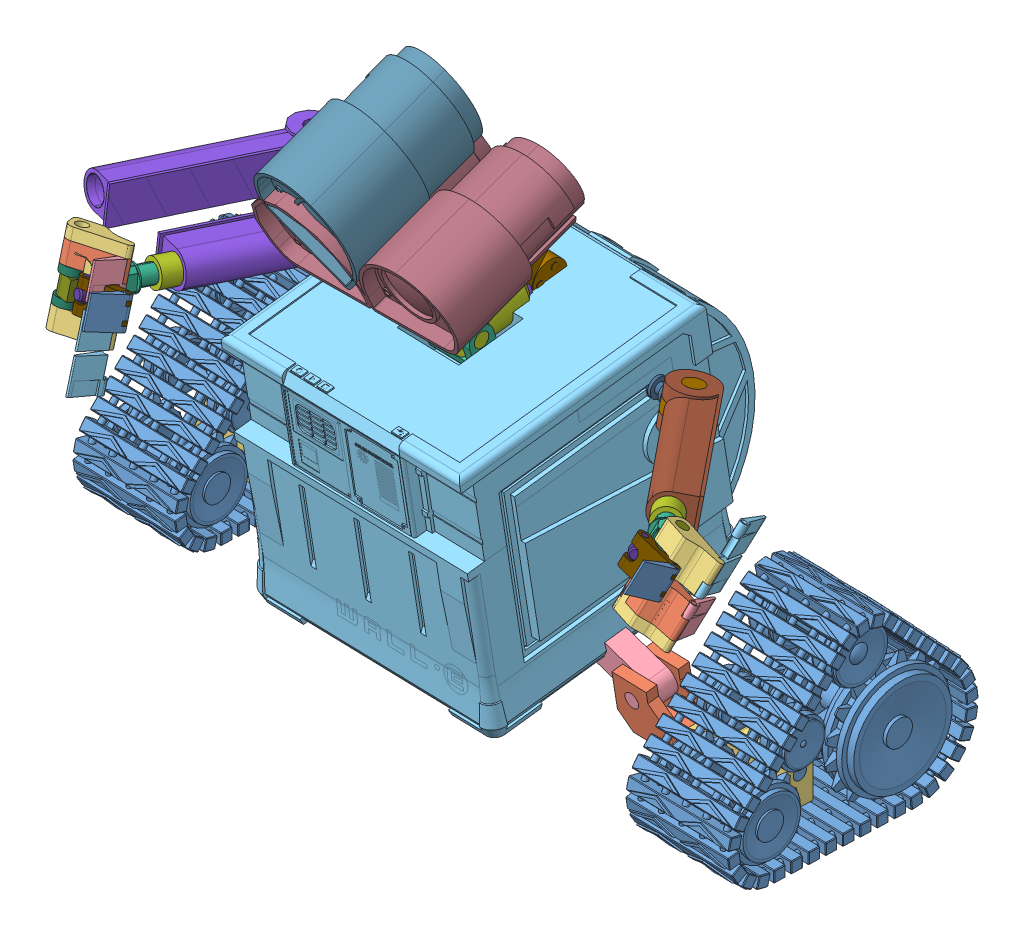
SolidWorks assembly Wall-E, configuration Default. Lengths in mm.
Overall size (1010.81 812.29 599.18).
52 component instances, 29 part files, 21 mates.
Components (placement in the parent):
- been links ^Wall-E-1: been links ^Wall-E [Default] at origin size (390.22 327.08 393.39) (virtual)
  - Leg2-1: Leg2 [Default] at (217.59 79.9141 -697.9774) x (0.99964 0 0.026846) z (-0.026526 -0.154085 0.987701) size (150 276.28 351.13)
  - Leg4-1: Leg4 [Default] at (37.1535 79.1519 -684.1405) x (0.99964 0 0.026846) z (-0.026526 -0.154085 0.987701) size (110 70 60)
  - Leg5-1: Leg5 [Default] at (37.2437 79.4124 -687.5004) x (0.99964 0 0.026846) z (-0.026846 0 0.99964) size (135 55 55.64)
  - Leg1-1: Leg1 [Default] at (-65.5734 118.3428 -680.7854) x (0.933881 -0.356281 -0.030501) z (-0.026526 -0.154085 0.987701) size (150 40 60)
- been rechts ^Wall-E-1: been rechts ^Wall-E [Default] at origin size (388.72 327.08 393.39) (virtual)
  - Leg2-1: Leg2 [Default] at (-587.65 80.7609 -719.4707) x (0.99964 0 0.026846) z (-0.026526 -0.154085 0.987701) size (150 276.28 351.13)
  - Leg4-1: Leg4 [Default] at (-408.2163 79.9987 -695.9692) x (-0.99964 0 -0.026846) z (0.026526 0.154085 -0.987701) size (110 70 60)
  - Leg5-1: Leg5 [Default] at (-408.126 80.2592 -699.329) x (-0.99964 0 -0.026846) z (0.026846 0 -0.99964) size (135 55 55.64)
  - Leg1-1: Leg1 [Default] at (-408.2163 79.9987 -695.9692) x (0.933903 0.348583 0.079461) z (-0.026526 -0.154085 0.987701) size (150 40 60)
- Body2-1: Body2 [Default] at (-185.4474 98.5817 -687.0875) x (0.99964 0 0.026846) z (-0.026526 -0.154085 0.987701) size (356.05 350.01 438.03)
- nek ^Wall-E-1: nek ^Wall-E [Default] at origin size (101.29 227.96 274.03) (virtual)
  - Face 1-1: Face 1 [Default] at (-186.7587 411.7959 -638.2602) x (0.99964 0 0.026846) z (-0.025632 -0.297291 0.954443) size (100 57 34)
  - Face2-1: Face2 [Default] at (-187.2764 433.7783 -618.9842) x (0.99964 0 0.026846) z (-0.004222 0.987555 0.157218) size (70 90 60)
  - Face3-1: Face3 [Default] at (-184.744 448.8007 -713.2782) x (0.999393 -0.026492 0.022619) z (0.022596 0.987199 0.157882) size (48 63.5 48)
  - Face4-1: Face4 [Default] at (-184.0949 452.6513 -737.4481) x (0.999393 -0.026492 0.022619) z (-0.034706 -0.812993 0.581238) size (46 104.21 107.04)
  - Face5-1: Face5 [Default] at (-184.2148 488.5606 -690.0912) x (0.999393 -0.026492 0.022619) z (-0.034706 -0.812993 0.581238) size (26 40 80)
  - Face6-1: Face6 [Default] at (-181.7451 567.8812 -706.3104) x (0.999393 -0.026492 0.022619) z (-0.031088 -0.385342 0.92225) size (26 40 16)
  - Face7-1: Face7 [Default] at (-196.9225 572.4115 -621.9798) x (0.628822 0.709675 0.317719) z (-0.031088 -0.385342 0.92225) size (16 32 195)
- Eye2-1: Eye2 [Default] at (-180.8434 590.1537 -689.9259) x (-0.995709 -0.068519 -0.062193) z (-0.031088 -0.385342 0.92225) size (300 112 205)
- Eye1-1: Eye1 [Default] at (-211.7673 599.5241 -687.0531) x (-0.765702 0.602248 0.225825) z (-0.031088 -0.385342 0.92225) size (171 112 205)
- hand rechts^Wall-E-1: hand rechts^Wall-E [Default] at origin size (178.73 141.75 438.57) (virtual)
  - Hand6-1: Hand6 [Default] at (-488.8219 432.8353 -441.3284) x (0.958516 0.111487 0.262331) z (0.283339 -0.272348 -0.919535) size (30 45 77)
  - Hand7-1: Hand7 [Default] at (-502.4222 445.908 -397.1907) x (-0.031071 0.955718 -0.292639) z (0.283339 -0.272348 -0.919535) size (100 30 24)
  - Hand8-1: Hand8 [Default] at (-489.9614 447.3574 -393.7804) x (-0.283339 0.272348 0.919535) z (-0.031071 0.955718 -0.292639) size (14 21 42)
  - Hand9-1: Hand9 [Default] at (-476.2495 448.9522 -390.0276) x (-0.031071 0.955718 -0.292639) z (-0.983175 0.023503 0.181146) size (42 16 63)
  - Hand10-1: Hand10 [Default] at (-427.0907 447.777 -399.0849) x (-0.031071 0.955718 -0.292639) z (0.366331 -0.261519 -0.892978) size (42 10 48.5)
  - Finger1-1: Finger1 [Default] at (-503.1212 467.4117 -403.7751) x (-0.031071 0.955718 -0.292639) z (0.928144 -0.081063 -0.363286) size (45.5 28 75)
  - Finger2-1: Finger2 [Default] at (-503.5873 481.7475 -408.1646) x (-0.031071 0.955718 -0.292639) z (0.928144 -0.081063 -0.363286) size (115 28 75)
  - Finger3-1: Finger3 [Default] at (-447.8069 465.4182 -416.1583) x (-0.031071 0.955718 -0.292639) z (-0.202696 0.280672 0.938156) size (45.5 10 46.5)
  - Finger4-1: Finger4 [Default] at (-444.5445 365.0678 -385.4313) x (-0.031071 0.955718 -0.292639) z (-0.202696 0.280672 0.938156) size (96 10 46.5)
  - Hand5-1: Hand5 [Default] at (-432.3821 407.2275 -637.7842) x (-0.958516 -0.111487 -0.262331) z (-0.275342 0.124151 0.953296) size (34 34 222)
  - Hand4-2: Hand4 [Default] at (-417.2383 400.3992 -690.2154) x (0.902126 0.376028 0.211591) z (-0.275342 0.124151 0.953296) size (38 38 212)
  - Hand3(1)-1: Hand3(1) [Default] at (-555.6288 387.3923 -794.5796) x (0.96134 0.032008 0.273497) z (-0.275342 0.124151 0.953296) size (220 52 284)
  - Hand2-2: Hand2 [Default] at (-365.8274 392.5136 -749.8536) x (-0.99964 0 -0.026846) z (0.026625 -0.128211 -0.991389) size (66 52 60)
  - Hand5-2: Hand5 [Default] at (-432.3821 407.2275 -637.7842) x (-0.958516 -0.111487 -0.262331) z (-0.275342 0.124151 0.953296) size (34 34 222)
  - Hand1-1: Hand1 [Default] at (-343.8353 392.5136 -749.263) x (-0.99964 0 -0.026846) z (0.026526 0.154085 -0.987701) size (28 26 26)
- hand links ^Wall-E-1: hand links ^Wall-E [Default] at origin size (367.56 153.47 392.14) (virtual)
  - Hand6-1: Hand6 [Default] at (239.4104 448.9953 -494.9651) x (-0.724333 0.462571 0.511244) z (-0.637873 -0.168208 -0.751548) size (30 45 77)
  - Hand7-1: Hand7 [Default] at (270.0283 457.0693 -458.8908) x (-0.261649 -0.870479 0.4169) z (-0.637873 -0.168208 -0.751548) size (100 30 24)
  - Hand8-1: Hand8 [Default] at (260.612 463.0827 -452.2446) x (-0.637873 -0.168208 -0.751548) z (0.261649 0.870479 -0.4169) size (14 21 42)
  - Hand9-1: Hand9 [Default] at (250.2501 469.7 -444.9311) x (-0.261649 -0.870479 0.4169) z (-0.964096 0.256027 -0.070493) size (42 16 63)
  - Hand10-1: Hand10 [Default] at (298.4549 456.8986 -441.4064) x (-0.261649 -0.870479 0.4169) z (0.227156 -0.475354 -0.849964) size (42 10 48.5)
  - Finger1-1: Finger1 [Default] at (264.1412 437.4835 -449.5105) x (-0.261649 -0.870479 0.4169) z (0.963343 -0.209023 0.168164) size (45.5 28 75)
  - Finger2-1: Finger2 [Default] at (260.2164 424.4264 -443.257) x (-0.261649 -0.870479 0.4169) z (0.963539 -0.210532 0.165135) size (115 28 75)
  - Finger3-1: Finger3 [Default] at (318.6216 421.7677 -448.1327) x (-0.261649 -0.870479 0.4169) z (-0.179663 -0.380471 -0.907173) size (45.5 10 46.5)
  - Finger4-1: Finger4 [Default] at (346.0763 513.0899 -492.0819) x (-0.261649 -0.870479 0.4169) z (-0.179663 -0.380471 -0.907173) size (96 10 46.5)
  - Hand5-1: Hand5 [Default] at (107.9275 413.2276 -649.4611) x (-0.724333 0.462571 0.511244) z (0.639296 0.172972 0.749254) size (34 34 222)
  - Hand4-2: Hand4 [Default] at (72.7662 403.7141 -690.67) x (0.646042 -0.649273 -0.40134) z (0.639296 0.172972 0.749254) size (38 38 212)
  - Hand3-1: Hand3 [Default] at (34.0285 392.5136 -739.1152) x (0.768936 -0.151625 -0.621086) z (0.639296 0.172972 0.749254) size (60 52 284)
  - Hand2-1: Hand2 [Default] at (-1.9586 392.5136 -740.0816) x (0.99964 0 0.026846) z (-0.026126 0.230021 0.972835) size (66 52 60)
  - Hand1-1: Hand1 [Default] at (-23.9506 392.5136 -740.6722) x (0.99964 0 0.026846) z (-0.026526 -0.154085 0.987701) size (28 26 26)
Mates (geometry in assembly coordinates):
- Parallel4: parallel: line of Body2-1 through (-276.0756 411.8438 -478.6591) axis (0.99964 0 0.026846); plane of assembly through (0 0 0) normal (0 1 0)
- LimitAngle1: limit planar angle = 2.356194 rad anti-aligned: plane of Eye2-1 through (-174.5582 594.4182 -698.7753) normal (0.087157 -0.920227 -0.381558); plane of Eye1-1 through (-216.0507 606.991 -694.9207) normal (-0.642444 -0.699148 -0.31378)
- Distance8: distance = 860.6652 mm: point of assembly; point of Eye1-1; plane of assembly
- Coincident102: coincident anti-aligned: plane of Assem3^Wall-E 1-1/Leg2-1 through (189.3959 0 -657.5753) normal (0 -1 0)
- Parallel7: parallel: line of Assem3^Wall-E 1-1/Leg5-1 through (247.6513 90.5258 -699.8562) axis (-0.026846 0 0.99964)
- Coincident104: coincident anti-aligned: circle of Assem3^Wall-E 1-1/Leg1-1; circle of Body2-1
- Coincident105: coincident anti-aligned: plane of Assem4^Wall-E 1-1/Leg2-1 through (-573.1709 0 -758.875) normal (0 -1 0)
- Coincident106: coincident aligned: plane of been links ^Wall-E 1-1/Leg2-1 through (226.7926 48.8557 -540.907) normal (-0.026526 -0.154085 0.987701); plane of Assem4^Wall-E 1-1/Leg2-1 through (-578.4474 49.7025 -562.4003) normal (-0.026526 -0.154085 0.987701)
- Parallel8: parallel anti-aligned: line of been links ^Wall-E 1-1/Leg4-1 through (61.2453 99.2308 -649.9876) axis (-0.99964 0 -0.026846); line of Assem4^Wall-E 1-1/Leg4-1 through (-434.1064 100.0775 -663.1586) axis (0.99964 0 0.026846)
- Distance18: distance = 140 mm: plane of Assem4^Wall-E 1-1/Leg4-1 through (-381.736 -81.0142 -750.7502) normal (0.99964 0 0.026846); plane of been links ^Wall-E 1-1/Leg4-1 through (12.0602 -91.1061 -681.0018) normal (-0.99964 0 -0.026846)
- Parallel9: parallel: line of Assem4^Wall-E 1-1/Leg5-1 through (-618.5336 91.3726 -686.9732) axis (0.026846 0 -0.99964)
- Coincident107: coincident anti-aligned: circle of Assem4^Wall-E 1-1/Leg1-1; circle of Body2-1
- Coincident108: coincident aligned: circle of Body2-1; circle of Assem5^Wall-E 1-1/Face 1-1
- Coincident109: coincident anti-aligned: circle of Assem5^Wall-E 1-1/Face7-1; circle of Eye2-1
- Coincident110: coincident aligned: circle of Assem5^Wall-E 1-1/Face7-1; circle of Eye1-1
- Coincident111: coincident anti-aligned: line of Body2-1 through (-347.6212 403.364 -757.2903) axis (-0.99964 0 -0.026846); line of hand rechts^Wall-E 1-1/Hand1-1 through (-353.619 403.364 -757.4514) axis (0.99964 0 0.026846)
- Coincident112: coincident anti-aligned: plane of Body2-1 through (-347.5426 384.5909 -760.2168) normal (-0.99964 0 -0.026846); plane of hand rechts^Wall-E 1-1/Hand1-1 through (-347.5426 384.5909 -760.2168) normal (0.99964 0 0.026846)
- Coincident113: coincident anti-aligned: plane of Body2-1 through (-347.5426 384.5909 -760.2168) normal (-0.004137 0.988058 0.15403); plane of hand rechts^Wall-E 1-1/Hand1-1 through (-353.5404 384.5909 -760.3779) normal (0.004137 -0.988058 -0.15403)
- Coincident114: coincident anti-aligned: plane of Body2-1 through (-19.6608 384.5909 -751.4113) normal (0.99964 0 0.026846); plane of hand links ^Wall-E 1-1/Hand1-1 through (-20.1648 381.6632 -732.645) normal (-0.99964 0 -0.026846)
- Coincident115: coincident anti-aligned: line of Body2-1 through (-19.7394 403.364 -748.4847) axis (0.99964 0 0.026846); line of hand links ^Wall-E 1-1/Hand1-1 through (-13.7416 403.364 -748.3237) axis (-0.99964 0 -0.026846)
- Coincident116: coincident anti-aligned: plane of Body2-1 through (-19.6608 384.5909 -751.4113) normal (-0.004137 0.988058 0.15403); plane of hand links ^Wall-E 1-1/Hand1-1 through (-14.1669 381.6632 -732.4839) normal (0.004137 -0.988058 -0.15403)
